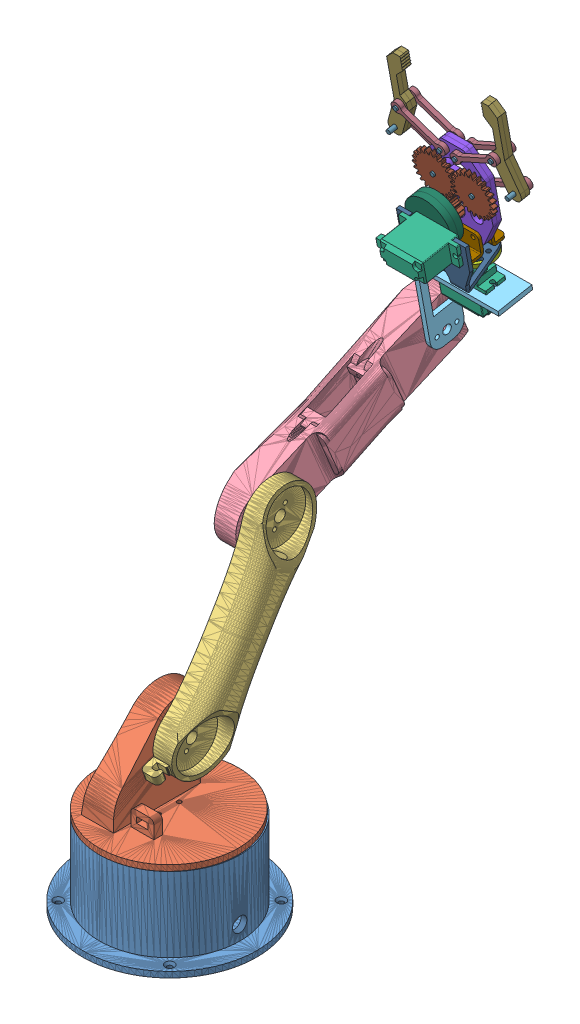
SolidWorks assembly Assembley 6DOF , configuration Default. Lengths in mm.
Overall size (150.31 442.87 274.6).
41 component instances, 15 part files, 13 mates.
Components (placement in the parent):
- Base-1: Base [Default] at (135.7768 64.5694 -121.8859) size (121.24 56 121.25)
- Waist-1: Waist [Default] at (132.604 108.4947 -121.6352) x (0.999997 0 -0.002568) z (0.002568 0 0.999997) size (96.99 64.78 97)
- Arm 01-2: Arm 01 [Default] at (134.6521 145.0306 -135.3467) x (-0.002204 -0.513676 -0.857982) z (0.999997 0 -0.002568) size (43.22 166.68 21)
- Arm 02-1: Arm 02 [Default] at (128.4605 248.043 -197.2835) x (-0.999827 0.016065 0.009374) z (-0.018447 -0.92103 -0.389055) size (27.46 167.91 39.33)
- Link1+Servo-1: Link1+Servo [Default] at (158.2074 351.0976 -307.1773) x (0.999997 0.000032 -0.002576) z (-0.002539 0.180322 -0.983604) size (60 83.25 26)
  - Link1-1: Link1 [Default] at origin size (60 61.3 24)
  - servo_small-1: servo_small [Predeterminado] at (-3.3 7 0) x (1 0 0) z (0 0 -1) size (40.9 36.75 14)
  - link1_adaptor-1: link1_adaptor [Default] at (6.43 -21.95 -0.39) x (0 0 -1) z (-1 0 0) size (26 9.2 26)
- Gripper_New-1: Gripper_New [Default] at (159.2454 361.6326 -265.1007) x (0.000433 0.983608 0.180321) z (0.002539 -0.180322 0.983604) size (118.35 115.85 64.02)
  - Assem4-1: Assem4 [Default] at (13.5 -5.5 -37.5997) x (0 1 0) z (-1 0 0) size (115.85 40.52 118.35) (flexible)
    - grip3-1: grip3 [Predeterminado] at origin size (41 3 62)
    - grip3-2: grip3 [Predeterminado] at (0 3 0) size (41 3 62)
    - grip51-1: grip51 [Default] at (0 6.5 -7) x (-1 0 0) z (0 0 -1) size (20 10 14)
    - grip51-2: grip51 [Default] at (0 -3.5 -7) x (1 0 0) z (0 0 -1) size (20 10 14)
    - grip2-1: grip2 [Predeterminado] at (-2.5 -23.5172 -25.1763) x (1 0 0) z (0 0 -1) size (48.01 40.52 34.68)
    - spur gear_am-1: spur gear_am [Metric - Spur gear 1.125M 24T 20PA 3FW ---S24N75H50L1.5N] at (13.5 -5.5 -37.5997) x (0 1 0) z (-0.908476 0 0.417936) size (3 29.07 29.07)
    - spur gear_am-2: spur gear_am [Metric - Spur gear 1.125M 24T 20PA 3FW ---S24N75H50L1.5N] at (-13.5 -5.5 -37.5997) x (0 1 0) z (0.956415 0 0.292011) size (3 29.07 29.07)
    - grip41-1: grip41 [Default] at (38.9026 1.5 -44.0456) x (0 -1 0) z (0.375 0 0.927025) size (3 20.79 60.37)
    - grip41-2: grip41 [Default] at (-38.4018 -1.5 -45.0831) x (0 1 0) z (-0.375 0 0.927025) size (3 20.79 60.37)
    - grip41-3: grip41 [Default] at (-38.4018 1.5 -45.0831) x (0 1 0) z (-0.375 0 0.927025) size (3 20.79 60.37)
    - grip41-4: grip41 [Default] at (38.9026 4.5 -44.0456) x (0 -1 0) z (0.375 0 0.927025) size (3 20.79 60.37)
    - grip11-1: grip11 [Default] at (-41.1619 5.5 -51.5932) x (0.89232 0 0.451404) z (-0.451404 0 0.89232) size (38 3 7)
    - grip11-2: grip11 [Default] at (13.5 5.5 -37.5997) x (0.908476 0 -0.417936) z (0.417936 0 0.908476) size (38 3 7)
    - grip11-3: grip11 [Default] at (5.25 5.5 -57.9943) x (0.908476 0 -0.417936) z (0.417936 0 0.908476) size (38 3 7)
    - grip11-4: grip11 [Default] at (5.25 -5.5 -57.9943) x (0.908476 0 -0.417936) z (0.417936 0 0.908476) size (38 3 7)
    - grip11-5: grip11 [Default] at (-32.9119 -5.5 -71.9878) x (0.89232 0 0.451404) z (-0.451404 0 0.89232) size (38 3 7)
    - grip11-6: grip11 [Default] at (-32.9119 5.5 -71.9878) x (0.89232 0 0.451404) z (-0.451404 0 0.89232) size (38 3 7)
    - pin1-1: pin1 [Default] at (-32.9119 1.5 -71.9878) size (3 16 3)
    - pin1-2: pin1 [Default] at (-41.1619 1.5 -51.5932) size (3 16 3)
    - pin1-3: pin1 [Default] at (-5.25 1.5 -57.9943) size (3 16 3)
    - pin1-4: pin1 [Default] at (-13.5 1.5 -37.5997) size (3 16 3)
    - pin1-5: pin1 [Default] at (33.4128 1.5 -70.9503) size (3 16 3)
    - pin1-6: pin1 [Default] at (41.6628 1.5 -50.5557) size (3 16 3)
    - pin1-7: pin1 [Default] at (5.25 1.5 -57.9943) size (3 16 3)
    - pin1-8: pin1 [Default] at (13.5 1.5 -37.5997) size (3 16 3)
  - gripper servo-1: gripper servo [Default] at (31.6763 -8 -2.0825) x (0 1 0) z (-1 0 0) size (48.24 52.75 36.62) (flexible)
    - servo_small-1: servo_small [Predeterminado] at origin size (40.9 36.75 14)
    - circular_coupling-1: circular_coupling [Default] at (9.73 16.3 0.39) x (0.987622 0 0.15685) z (-0.15685 0 0.987622) size (32 4.25 32)
    - circular_coupling-2: circular_coupling [Default] at (9.73 24.8 0.39) x (-0.987622 0 -0.15685) z (-0.15685 0 0.987622) size (32 4.25 32)
    - spur gear_am-4: spur gear_am [Metric - Spur gear 1.125M 12T 20PA 10FW ---S12N75H50L3N] at (9.73 35 0.39) x (0 -1 0) z (0.774402 0 -0.632694) size (10 15.31 15.31)
    - pin1-1: pin1 [Default] at (9.73 30.75 0.39) x (0.917663 0 0.397359) z (-0.397359 0 0.917663) size (3 16 3)
Mates (geometry in assembly coordinates):
- Coincident1: coincident anti-aligned: plane of Base-1 through (135.7768 104.4946 -121.8859) normal (0 1 0); plane of Waist-1 through (132.604 104.4946 -121.6352) normal (0 -1 0)
- Coincident2: coincident aligned: line of Base-1 through (132.812 104.4946 -73.0524) axis (0 -1 0); line of Waist-1 through (132.812 108.4946 -73.0524) axis (0 -1 0)
- Parallel4: parallel aligned: line of Base-1 through (132.812 104.4946 -171.0524) axis (-0.999453 0 0.033062); line of Waist-1 through (132.5628 108.4946 -170.0521) axis (-0.999453 0 0.033062)
- Coincident12: coincident anti-aligned: plane of Waist-1 through (128.6872 108.4947 -121.6251) normal (0.999997 0 -0.002568); plane of Arm 01-2 through (128.652 145.0306 -135.3313) normal (-0.999997 0 0.002568)
- Parallel11: parallel aligned: line of Waist-1 through (126.6286 144.7711 -144.4552) axis (0.000183 0.997453 0.071333); line of Arm 01-2 through (128.6419 144.7645 -139.2851) axis (0.000183 0.997453 0.071333)
- Lock2: lock: unknown of Waist-1; unknown of Arm 01-2
- Coincident21: coincident anti-aligned: plane of Arm 01-2 through (128.652 145.0306 -135.3313) normal (-0.999997 0 0.002568); plane of Arm 02-1 through (128.4929 248.043 -197.2835) normal (0.999997 0 -0.002568)
- Lock3: lock: unknown of Arm 01-2; unknown of Arm 02-1
- Coincident30: coincident anti-aligned: plane of Arm 02-1 through (128.4936 248.043 -197.2835) normal (0.999997 0.000032 -0.002576); plane of Link1+Servo-1/Link1-1 through (128.1756 350.0146 -319.4983) normal (-0.999997 -0.000032 0.002576)
- Lock5: lock: unknown of Arm 02-1; unknown of Link1+Servo-1/Link1-1
- Coincident32: coincident: plane of Link1+Servo-1/link1_adaptor-1 through (164.6479 372.6177 -302.8522) normal (0.000433 0.983608 0.180321); plane of Gripper_New-1/Assem4-1/grip2-1 through (163.0021 372.645 -302.9972) normal (-0.000433 -0.983608 -0.180321)
- Concentric2: concentric: circle of Link1+Servo-1/link1_adaptor-1; circle of Gripper_New-1/Assem4-1/grip51-1
- Concentric3: concentric aligned: circle of Link1+Servo-1/link1_adaptor-1; circle of Gripper_New-1/Assem4-1/grip51-2
